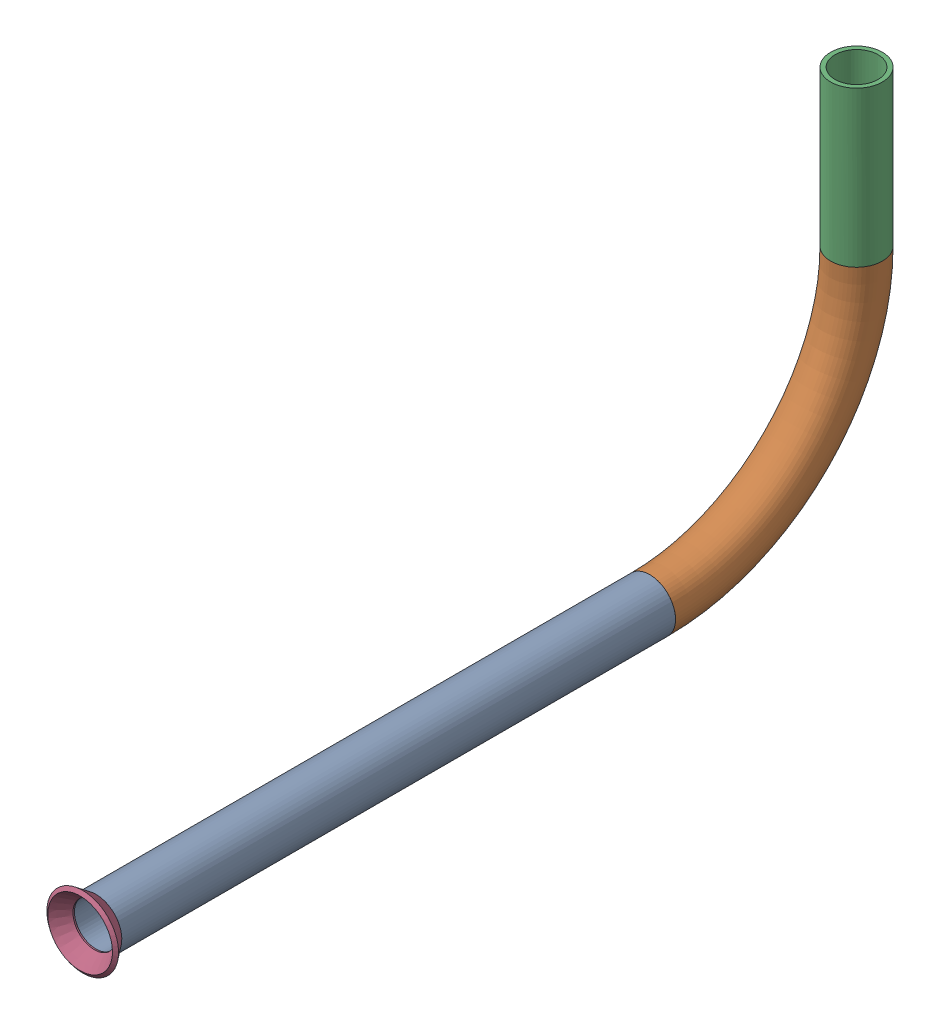
SolidWorks assembly Pipe 25, configuration Default. Lengths in mm.
Overall size (17.59 97.7 197.04).
2 component instances, 2 part files, 2 mates.
Components (placement in the parent):
- Pipe 25.1-1: Pipe 25.1 [Default<As Machined>] at (-964.8447 1090.8032 -46.7287) size (12.7 95.25 193.16)
- Flared pipe end - .5 inch-1: Flared pipe end - .5 inch [Default<As Machined>] at (-964.8447 1690.7632 256.4359) size (17.59 17.59 3.89)
Mates (geometry in assembly coordinates):
- Coincident1221: coincident: plane of Pipe 25.1-1 through (-964.8447 1690.7632 256.4359) normal (0 0 1); plane of Flared pipe end - .5 inch-1 through (-964.8447 1696.0464 256.4359) normal (0 0 -1)
- Concentric726: concentric: circle of Pipe 25.1-1; circle of Flared pipe end - .5 inch-1
